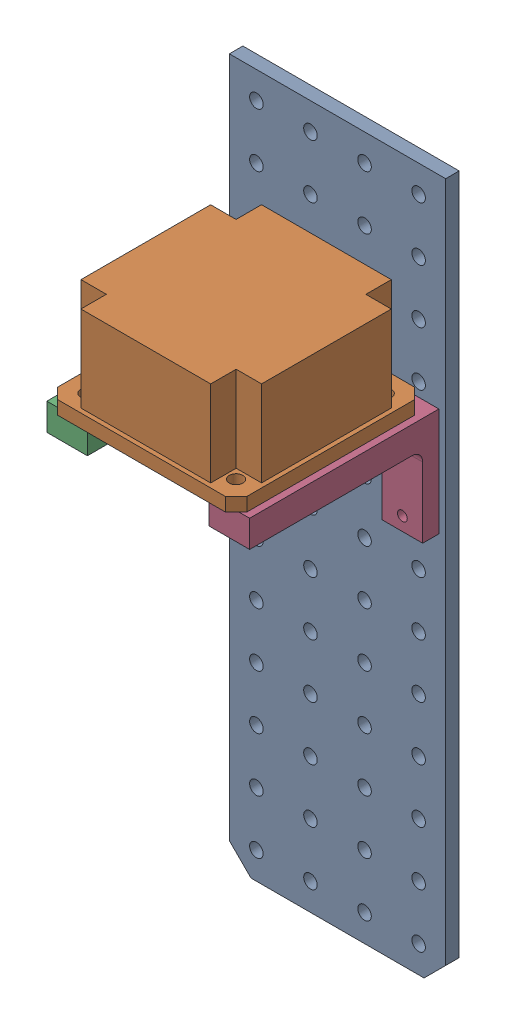
SolidWorks assembly Assem1, configuration Default. Lengths in mm.
Overall size (50.8 165.1 49.21).
3 component instances, 3 part files, 6 mates.
Components (placement in the parent):
- vertical_plate-1: vertical_plate [Default] at (-13.1189 -2.2011 8.4181) size (50.8 165.1 3.17)
- switch-1: switch [Default] at (-13.1189 32.7239 35.4056) size (44.45 23.32 44.45)
- dual-bracket-1: dual-bracket [Default] at (-13.1189 20.0239 56.0431) x (-1 0 0) z (0 0 -1) size (47.62 25.4 44.45)
Mates (geometry in assembly coordinates):
- Coincident5: coincident anti-aligned: plane of vertical_plate-1 through (-13.1189 -2.2011 11.5931) normal (0 0 1); plane of dual-bracket-1 through (-13.1189 20.0239 11.5931) normal (0 0 -1)
- Parallel2: parallel aligned: plane of vertical_plate-1 through (-38.5189 80.3489 11.5931) normal (0 1 0); plane of dual-bracket-1 through (10.6936 32.7239 11.5931) normal (0 1 0)
- Concentric6: concentric anti-aligned: circle of vertical_plate-1; circle of dual-bracket-1
- Coincident7: coincident anti-aligned: plane of switch-1 through (-13.1189 32.7239 35.4056) normal (0 -1 0); plane of dual-bracket-1 through (10.6936 32.7239 11.5931) normal (0 1 0)
- Concentric7: concentric anti-aligned: circle of switch-1; circle of dual-bracket-1
- Concentric8: concentric anti-aligned: circle of switch-1; circle of dual-bracket-1
